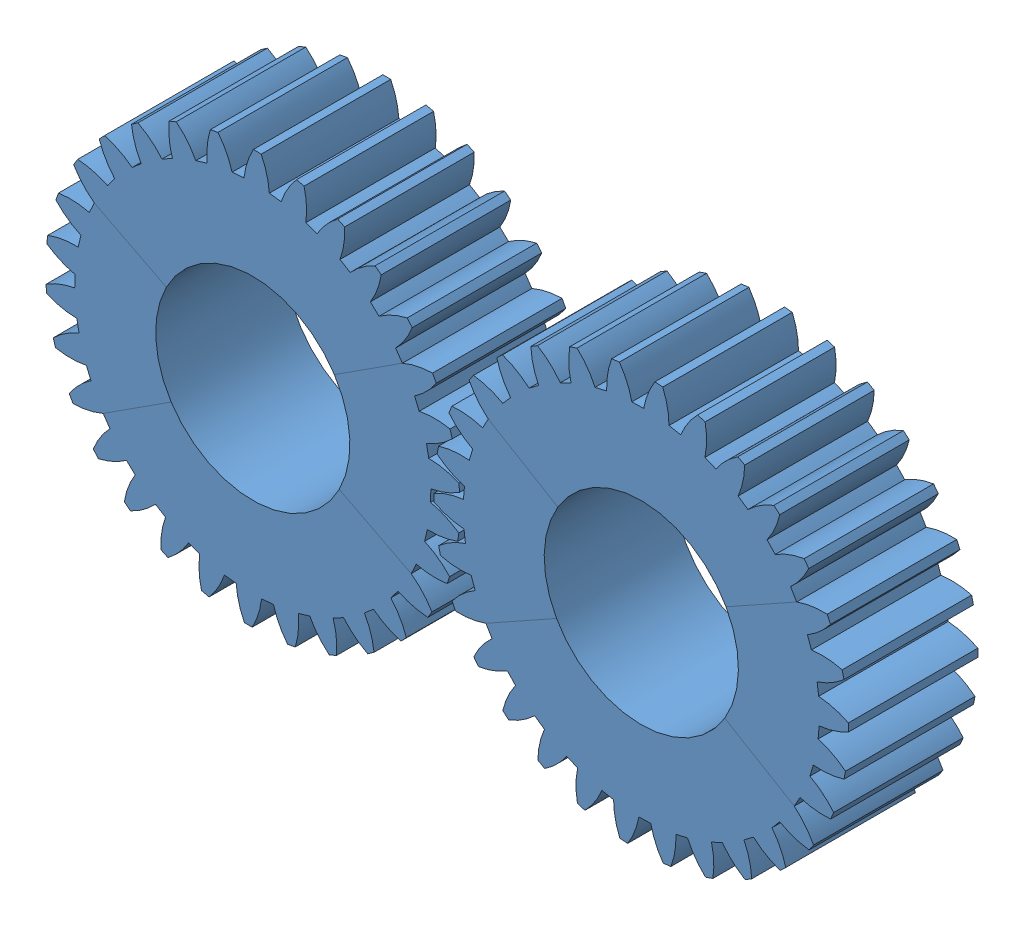
SolidWorks assembly Gear_Assembly, configuration Default. Lengths in mm.
Overall size (142.39 83.68 20).
2 component instances, 1 part files, 5 mates.
Components (placement in the parent):
- Part3^Gear_Assembly-1: Part3^Gear_Assembly [Default] at (60.0102 0 -20) x (0.386725 -0.922195 0) z (0 0 1) size (64 63.76 20) (virtual)
- Part3^Gear_Assembly-2: Part3^Gear_Assembly [Default] at (120.0102 0 -20) x (0.32783 -0.944737 0) z (0 0 1) size (64 63.76 20) (virtual)
Mates (geometry in assembly coordinates):
- Coincident13: coincident: line of Part3^Gear_Assembly-1 through (60.0102 0 0) axis (0 0 -1)
- Coincident14: coincident: line of Part3^Gear_Assembly-2 through (120.0102 0 0) axis (0 0 -1)
- Coincident15: coincident aligned: plane of Part3^Gear_Assembly-2 through (129.0514 -10.8137 0) normal (0 0 1); plane of Part3^Gear_Assembly-1 through (69.715 -10.2224 0) normal (0 0 1)
- Distance3: distance = 30 mm: cylinder of Part3^Gear_Assembly-1 through (60.0102 0 -20) axis (0 0 1) radius 15; cylinder of Part3^Gear_Assembly-2 through (120.0102 0 -20) axis (0 0 1) radius 15
- Coincident16: coincident aligned: plane of Part3^Gear_Assembly-1 through (69.715 -10.2224 0) normal (0 0 1)
